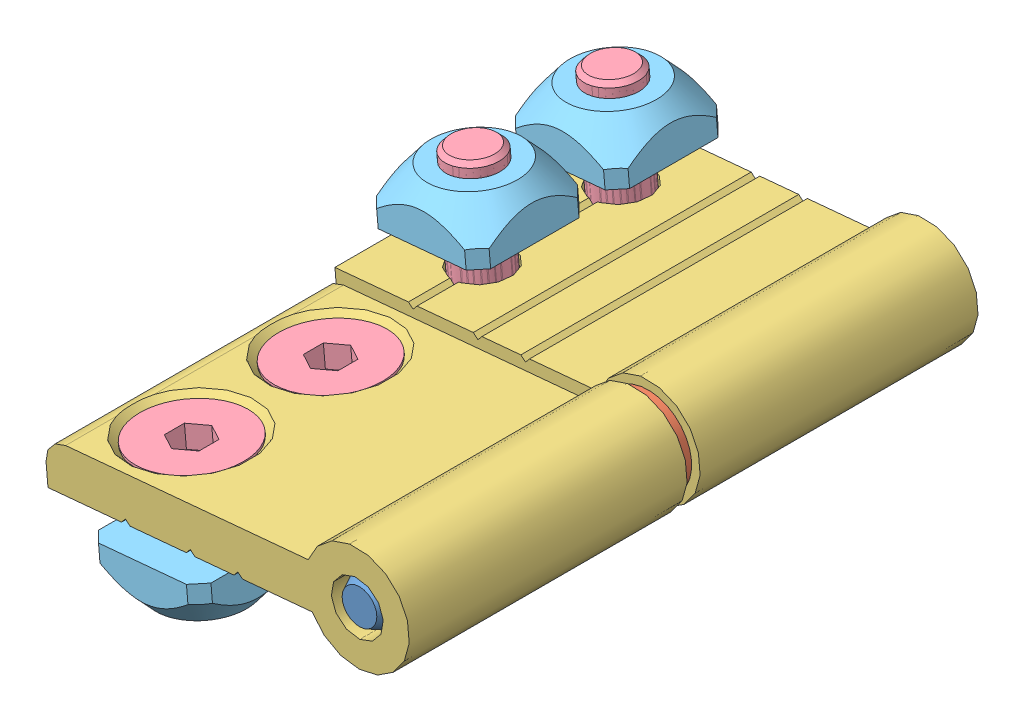
SolidWorks assembly 21.1378 HINGE L 45_45 LEFT HAND, configuration Default. Lengths in mm.
Overall size (42.93 28.99 65.5).
12 component instances, 5 part files, 22 mates.
Components (placement in the parent):
- 21.1096 HINGE PIN-1: 21.1096 HINGE PIN [Default] at origin size (6.07 6.07 65)
- 21.1096 HINGE WASHER-1: 21.1096 HINGE WASHER [Default] at (0 0 31.75) x (0.995445 -0.095341 0) z (0 0 1) size (10 10 1.5)
- 21.1378 HINGE L 45 AL BLOCK-1: 21.1378 HINGE L 45 AL BLOCK [Default] at (0 0 15.75) x (-0.995759 -0.091997 0) z (0 0 1) size (42 12 32)
- 21.1378 HINGE L 45 AL BLOCK-2: 21.1378 HINGE L 45 AL BLOCK [Default] at (0 0 49.25) x (-0.995759 -0.091997 0) z (0 0 -1) size (42 12 32)
- 21.1506 M6x16 C'SUNK-1: 21.1506 M6x16 C'SUNK [Default] at (-26.7015 -4.4754 7.75) x (0.995759 0.091997 0) z (0.091997 -0.995759 0) size (12 12 16)
- 21.1506 M6x16 C'SUNK-2: 21.1506 M6x16 C'SUNK [Default] at (-27.0695 -0.4924 41.25) x (0.995759 0.091997 0) z (-0.091997 0.995759 0) size (12 12 16)
- 21.1506 M6x16 C'SUNK-3: 21.1506 M6x16 C'SUNK [Default] at (-27.0695 -0.4924 57.25) x (0.995759 0.091997 0) z (-0.091997 0.995759 0) size (12 12 16)
- 21.1506 M6x16 C'SUNK-4: 21.1506 M6x16 C'SUNK [Default] at (-26.7015 -4.4754 23.75) x (0.995689 0.091991 0.011859) z (0.091997 -0.995759 0) size (12 12 16)
- 21.1330 M6 SQUARE NUT-1: 21.1330 M6 SQUARE NUT [Default] at (-26.2415 -9.4542 41.25) x (0.995759 0.091997 0) z (-0.091997 0.995759 0) size (13 13 5.5)
- 21.1330 M6 SQUARE NUT-2: 21.1330 M6 SQUARE NUT [Default] at (-26.2415 -9.4542 57.25) x (0 0 1) z (-0.091997 0.995759 0) size (13 13 5.5)
- 21.1330 M6 SQUARE NUT-3: 21.1330 M6 SQUARE NUT [Default] at (-27.5295 4.4864 7.75) x (0.995759 0.091997 0) z (0.091997 -0.995759 0) size (13 13 5.5)
- 21.1330 M6 SQUARE NUT-4: 21.1330 M6 SQUARE NUT [Default] at (-27.5295 4.4864 23.75) x (0.995759 0.091997 0) z (0.091997 -0.995759 0) size (13 13 5.5)
Mates (geometry in assembly coordinates):
- Coincident1: coincident anti-aligned: line of 21.1096 HINGE PIN-1 through (0 0 2) axis (0 0 1); line of 21.1378 HINGE L 45 AL BLOCK-1 through (0 0 31.75) axis (0 0 -1)
- Distance1: distance = 0.25 mm aligned: plane of 21.1378 HINGE L 45 AL BLOCK-1 through (-14.3326 -1.2703 -0.25) normal (0 0 -1); plane of 21.1096 HINGE PIN-1 through (0 0 0) normal (0 0 -1)
- Coincident3: coincident aligned: line of 21.1096 HINGE PIN-1 through (0 0 33.25) axis (0 0 1); line of 21.1096 HINGE WASHER-1 through (0 0 31.75) axis (0 0 1)
- Coincident4: coincident anti-aligned: plane of 21.1096 HINGE WASHER-1 through (0 0 31.75) normal (0 0 -1); plane of 21.1378 HINGE L 45 AL BLOCK-1 through (-14.3326 -1.2703 31.75) normal (0 0 1)
- Coincident5: coincident aligned: line of 21.1378 HINGE L 45 AL BLOCK-2 through (0 0 33.25) axis (0 0 1); line of 21.1096 HINGE PIN-1 through (0 0 33.25) axis (0 0 1)
- Coincident6: coincident anti-aligned: plane of 21.1096 HINGE WASHER-1 through (0 0 33.25) normal (0 0 1); plane of 21.1378 HINGE L 45 AL BLOCK-2 through (-14.3227 -1.3772 33.25) normal (0 0 -1)
- Coincident7: coincident aligned: line of 21.1506 M6x16 C'SUNK-3 through (-26.7545 -3.9021 57.25) axis (0.091997 -0.995759 0); line of 21.1378 HINGE L 45 AL BLOCK-2 through (-26.7843 -3.5793 57.25) axis (0.091997 -0.995759 0)
- Coincident8: coincident aligned: line of 21.1506 M6x16 C'SUNK-2 through (-26.7545 -3.9021 41.25) axis (0.091997 -0.995759 0); line of 21.1378 HINGE L 45 AL BLOCK-2 through (-27.1155 0.0055 41.25) axis (0.091997 -0.995759 0)
- Coincident9: coincident aligned: line of 21.1378 HINGE L 45 AL BLOCK-1 through (-26.6555 -4.9733 7.75) axis (-0.091997 0.995759 0); line of 21.1506 M6x16 C'SUNK-1 through (-26.8558 -2.8056 7.75) axis (-0.091997 0.995759 0)
- Coincident10: coincident aligned: line of 21.1506 M6x16 C'SUNK-4 through (-27.0165 -1.0657 23.75) axis (-0.091997 0.995759 0); line of 21.1378 HINGE L 45 AL BLOCK-1 through (-26.6555 -4.9733 23.75) axis (-0.091997 0.995759 0)
- Distance2: distance = 0.5 mm aligned: plane of 21.1506 M6x16 C'SUNK-2 through (-24.0822 -0.2164 41.25) normal (-0.091997 0.995759 0); plane of 21.1378 HINGE L 45 AL BLOCK-2 through (-33.5879 -0.5925 49.25) normal (-0.091997 0.995759 0)
- Distance3: distance = 0.5 mm aligned: plane of 21.1506 M6x16 C'SUNK-3 through (-24.0822 -0.2164 57.25) normal (-0.091997 0.995759 0); plane of 21.1378 HINGE L 45 AL BLOCK-2 through (-33.5879 -0.5925 49.25) normal (-0.091997 0.995759 0)
- Distance4: distance = 0.5 mm aligned: plane of 21.1506 M6x16 C'SUNK-1 through (-23.7142 -4.1994 7.75) normal (0.091997 -0.995759 0); plane of 21.1378 HINGE L 45 AL BLOCK-1 through (-33.1279 -5.5713 15.75) normal (0.091997 -0.995759 0)
- Coincident14: coincident aligned: plane of 21.1506 M6x16 C'SUNK-1 through (-23.7142 -4.1994 7.75) normal (0.091997 -0.995759 0); plane of 21.1506 M6x16 C'SUNK-4 through (-23.7144 -4.1995 23.7856) normal (0.091997 -0.995759 0)
- Coincident15: coincident aligned: line of 21.1330 M6 SQUARE NUT-3 through (-27.7073 6.4115 7.75) axis (-0.091997 0.995759 0); line of 21.1506 M6x16 C'SUNK-1 through (-28.1275 10.9588 7.75) axis (-0.091997 0.995759 0)
- Coincident16: coincident aligned: line of 21.1506 M6x16 C'SUNK-4 through (-27.0165 -1.0657 23.75) axis (-0.091997 0.995759 0); line of 21.1330 M6 SQUARE NUT-4 through (-27.7073 6.4115 23.75) axis (-0.091997 0.995759 0)
- Distance5: distance = 4.5 mm anti-aligned: plane of 21.1330 M6 SQUARE NUT-4 through (-27.5295 4.4864 23.75) normal (0.091997 -0.995759 0); plane of 21.1378 HINGE L 45 AL BLOCK-1 through (-20.1452 0.6495 15.75) normal (-0.091997 0.995759 0)
- Coincident18: coincident aligned: plane of 21.1330 M6 SQUARE NUT-3 through (-28.0355 9.9631 7.75) normal (-0.091997 0.995759 0); plane of 21.1330 M6 SQUARE NUT-4 through (-28.0355 9.9631 23.75) normal (-0.091997 0.995759 0)
- Coincident19: coincident aligned: line of 21.1330 M6 SQUARE NUT-1 through (-26.0637 -11.3794 41.25) axis (0.091997 -0.995759 0); line of 21.1506 M6x16 C'SUNK-2 through (-26.7545 -3.9021 41.25) axis (0.091997 -0.995759 0)
- Coincident20: coincident aligned: line of 21.1330 M6 SQUARE NUT-2 through (-26.0637 -11.3794 57.25) axis (0.091997 -0.995759 0); line of 21.1506 M6x16 C'SUNK-3 through (-26.7545 -3.9021 57.25) axis (0.091997 -0.995759 0)
- Distance6: distance = 4.5 mm anti-aligned: plane of 21.1330 M6 SQUARE NUT-1 through (-26.2415 -9.4542 41.25) normal (-0.091997 0.995759 0); plane of 21.1378 HINGE L 45 AL BLOCK-2 through (-27.1534 -5.0193 49.25) normal (0.091997 -0.995759 0)
- Distance7: distance = 4.5 mm anti-aligned: plane of 21.1378 HINGE L 45 AL BLOCK-2 through (-27.1534 -5.0193 49.25) normal (0.091997 -0.995759 0); plane of 21.1330 M6 SQUARE NUT-2 through (-26.2415 -9.4542 57.25) normal (-0.091997 0.995759 0)
